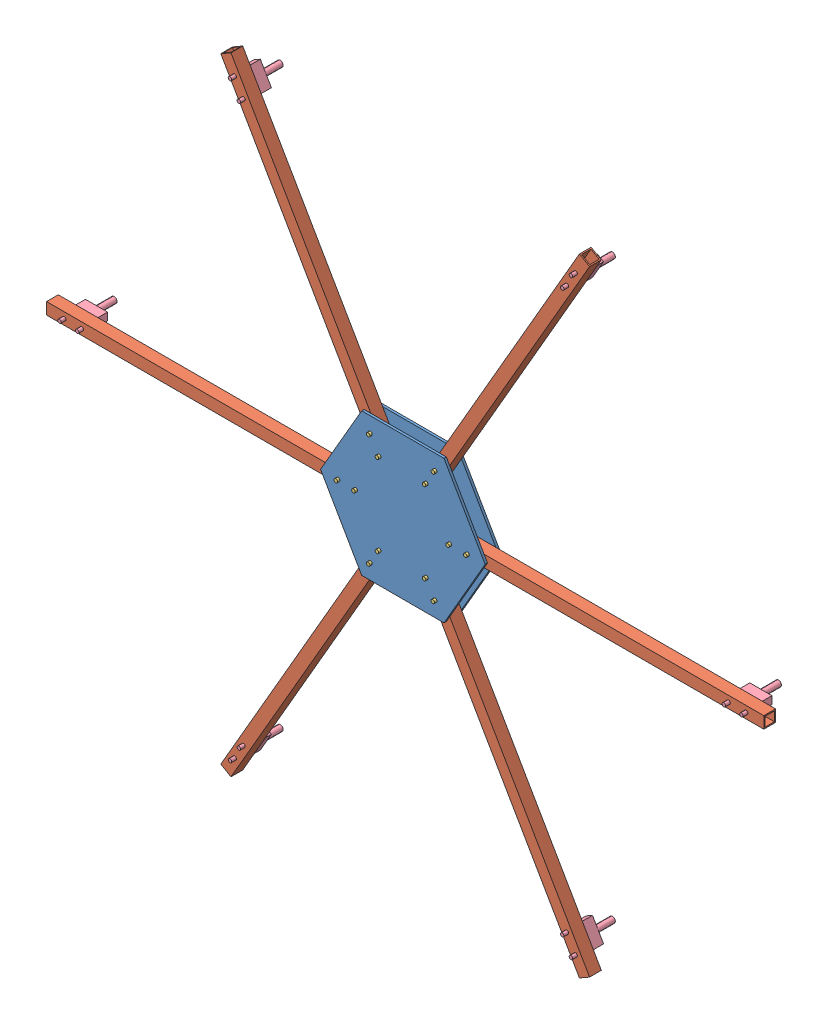
SolidWorks assembly carbonframe, configuration Default. Lengths in mm.
Overall size (610.11 533.37 39).
26 component instances, 4 part files, 63 mates.
Components (placement in the parent):
- carbonfiberplate-1: carbonfiberplate [Default] at (50.332 74.6713 106.3835) size (140 121.24 2)
- carbonfiberarm-2: carbonfiberarm [Default] at (-254.7472 74.717 113.3835) x (0 1 0) z (1 0 0) size (10 10 280)
- carbonfiberarm-3: carbonfiberarm [Default] at (-102.2208 -189.4665 113.3835) x (0.866025 -0.5 0) z (0.5 0.866025 0) size (10 10 280)
- carbonfiberarm-4: carbonfiberarm [Default] at (355.3584 74.717 113.3835) x (0 1 0) z (-1 0 0) size (10 10 280)
- carbonfiberarm-5: carbonfiberarm [Default] at (37.7792 96.4134 113.3835) x (0.866025 0.5 0) z (-0.5 0.866025 0) size (10 10 280)
- carbonfiberarm-6: carbonfiberarm [Default] at (62.832 96.4134 113.3835) x (0.866025 -0.5 0) z (0.5 0.866025 0) size (10 10 280)
- carbonfiberarm-7: carbonfiberarm [Default] at (62.832 53.0207 113.3835) x (0.866025 0.5 0) z (0.5 -0.866025 0) size (10 10 280)
- carbonfiberplate-2: carbonfiberplate [Default] at (50.332 74.6713 118.3835) size (140 121.24 2)
- nutfrcarbonframe-1: nutfrcarbonframe [Default] at (22.7792 122.3942 103.3835) size (6 6 19)
- nutfrcarbonframe-2: nutfrcarbonframe [Default] at (30.2792 109.4038 103.3835) size (6 6 19)
- nutfrcarbonframe-3: nutfrcarbonframe [Default] at (77.832 122.3942 103.3835) size (6 6 19)
- nutfrcarbonframe-4: nutfrcarbonframe [Default] at (70.332 109.4038 103.3835) size (6 6 19)
- nutfrcarbonframe-5: nutfrcarbonframe [Default] at (90.3584 74.717 103.3835) size (6 6 19)
- nutfrcarbonframe-6: nutfrcarbonframe [Default] at (70.332 40.0303 103.3835) size (6 6 19)
- nutfrcarbonframe-7: nutfrcarbonframe [Default] at (105.3584 74.717 103.3835) x (0.627916 0.778281 0) z (0 0 1) size (6 6 19)
- nutfrcarbonframe-8: nutfrcarbonframe [Default] at (77.832 27.0399 103.3835) x (0.998985 0.045038 0) z (0 0 1) size (6 6 19)
- nutfrcarbonframe-9: nutfrcarbonframe [Default] at (30.2792 40.0303 103.3835) size (6 6 19)
- nutfrcarbonframe-10: nutfrcarbonframe [Default] at (22.7792 27.0399 103.3835) size (6 6 19)
- nutfrcarbonframe-11: nutfrcarbonframe [Default] at (10.2528 74.717 103.3835) size (6 6 19)
- nutfrcarbonframe-12: nutfrcarbonframe [Default] at (-4.7472 74.717 103.3835) size (6 6 19)
- motorcf-1: motorcf [Default] at (-87.2208 -163.4857 122.3835) x (-0.5 -0.866025 0) z (0 0 -1) size (18.85 6.42 39)
- motorcf-2: motorcf [Default] at (-224.7472 74.717 122.3835) x (-1 0 0) z (0 0 -1) size (18.85 6.42 39)
- motorcf-3: motorcf [Default] at (340.3584 74.717 122.3835) x (-1 0 0) z (0 0 -1) size (18.85 6.42 39)
- motorcf-4: motorcf [Default] at (187.832 -163.4857 122.3835) x (0.5 -0.866025 0) z (0 0 -1) size (18.85 6.42 39)
- motorcf-5: motorcf [Default] at (195.332 325.9101 122.3835) x (-0.5 -0.866025 0) z (0 0 -1) size (18.85 6.42 39)
- motorcf-6: motorcf [Default] at (-87.2208 312.9197 122.3835) x (-0.5 0.866025 0) z (0 0 -1) size (18.85 6.42 39)
Mates (geometry in assembly coordinates):
- Coincident1: coincident anti-aligned: plane of carbonfiberplate-1 through (50.332 74.6713 108.3835) normal (0 0 1); plane of carbonfiberarm-2 through (25.2528 69.717 108.3835) normal (0 0 -1)
- Coincident8: coincident aligned: circle of carbonfiberplate-1; circle of carbonfiberarm-2
- Coincident4: coincident anti-aligned: plane of carbonfiberplate-1 through (50.332 74.6713 108.3835) normal (0 0 1); plane of carbonfiberarm-3 through (33.4491 55.5207 108.3835) normal (0 0 -1)
- Coincident5: coincident anti-aligned: circle of carbonfiberplate-1; circle of carbonfiberarm-3
- Coincident6: coincident anti-aligned: circle of carbonfiberplate-1; circle of carbonfiberarm-3
- Coincident7: coincident anti-aligned: plane of carbonfiberplate-1 through (50.332 74.6713 108.3835) normal (0 0 1); plane of carbonfiberarm-5 through (-106.5509 336.4005 108.3835) normal (0 0 -1)
- Coincident9: coincident aligned: circle of carbonfiberplate-1; circle of carbonfiberarm-2
- Coincident10: coincident anti-aligned: circle of carbonfiberplate-1; circle of carbonfiberarm-5
- Coincident11: coincident anti-aligned: circle of carbonfiberplate-1; circle of carbonfiberarm-5
- Coincident12: coincident anti-aligned: plane of carbonfiberplate-1 through (50.332 74.6713 108.3835) normal (0 0 1); plane of carbonfiberarm-4 through (75.3584 69.717 108.3835) normal (0 0 -1)
- Coincident13: coincident anti-aligned: circle of carbonfiberplate-1; circle of carbonfiberarm-4
- Coincident14: coincident anti-aligned: circle of carbonfiberplate-1; circle of carbonfiberarm-4
- Coincident15: coincident anti-aligned: plane of carbonfiberplate-1 through (50.332 74.6713 108.3835) normal (0 0 1); plane of carbonfiberarm-6 through (198.5019 341.4005 108.3835) normal (0 0 -1)
- Coincident16: coincident anti-aligned: circle of carbonfiberplate-1; circle of carbonfiberarm-6
- Coincident17: coincident anti-aligned: circle of carbonfiberplate-1; circle of carbonfiberarm-6
- Coincident18: coincident anti-aligned: plane of carbonfiberplate-1 through (50.332 74.6713 108.3835) normal (0 0 1); plane of carbonfiberarm-7 through (198.5019 -191.9665 108.3835) normal (0 0 -1)
- Coincident19: coincident aligned: circle of carbonfiberplate-1; circle of carbonfiberarm-7
- Coincident20: coincident aligned: circle of carbonfiberplate-1; circle of carbonfiberarm-7
- Coincident21: coincident anti-aligned: plane of carbonfiberarm-6 through (198.5019 341.4005 118.3835) normal (0 0 1); plane of carbonfiberplate-2 through (50.332 74.6713 118.3835) normal (0 0 -1)
- Coincident22: coincident anti-aligned: circle of carbonfiberarm-4; circle of carbonfiberplate-2
- Coincident23: coincident anti-aligned: circle of carbonfiberarm-4; circle of carbonfiberplate-2
- Concentric5: concentric aligned: cylinder of carbonfiberplate-1 through (22.7792 122.3942 108.3835) axis (0 0 -1) radius 1.5; cylinder of nutfrcarbonframe-1 through (22.7792 122.3942 122.3835) axis (0 0 -1) radius 1.5
- Coincident24: coincident anti-aligned: plane of carbonfiberplate-1 through (50.332 74.6713 106.3835) normal (0 0 -1); plane of nutfrcarbonframe-1 through (22.7792 122.3942 106.3835) normal (0 0 1)
- Concentric6: concentric aligned: cylinder of carbonfiberplate-1 through (30.2792 109.4038 108.3835) axis (0 0 -1) radius 1.5; cylinder of nutfrcarbonframe-2 through (30.2792 109.4038 122.3835) axis (0 0 -1) radius 1.5
- Coincident25: coincident anti-aligned: plane of carbonfiberplate-1 through (50.332 74.6713 106.3835) normal (0 0 -1); plane of nutfrcarbonframe-2 through (30.2792 109.4038 106.3835) normal (0 0 1)
- Concentric7: concentric aligned: cylinder of carbonfiberplate-1 through (77.832 122.3942 108.3835) axis (0 0 -1) radius 1.5; cylinder of nutfrcarbonframe-3 through (77.832 122.3942 122.3835) axis (0 0 -1) radius 1.5
- Coincident26: coincident anti-aligned: plane of carbonfiberplate-1 through (50.332 74.6713 106.3835) normal (0 0 -1); plane of nutfrcarbonframe-3 through (77.832 122.3942 106.3835) normal (0 0 1)
- Concentric8: concentric aligned: cylinder of carbonfiberplate-1 through (70.332 109.4038 108.3835) axis (0 0 -1) radius 1.5; cylinder of nutfrcarbonframe-4 through (70.332 109.4038 122.3835) axis (0 0 -1) radius 1.5
- Coincident27: coincident anti-aligned: plane of carbonfiberplate-1 through (50.332 74.6713 106.3835) normal (0 0 -1); plane of nutfrcarbonframe-4 through (70.332 109.4038 106.3835) normal (0 0 1)
- Concentric9: concentric aligned: cylinder of carbonfiberplate-1 through (90.3584 74.717 108.3835) axis (0 0 -1) radius 1.5; cylinder of nutfrcarbonframe-5 through (90.3584 74.717 122.3835) axis (0 0 -1) radius 1.5
- Coincident28: coincident anti-aligned: plane of carbonfiberplate-1 through (50.332 74.6713 106.3835) normal (0 0 -1); plane of nutfrcarbonframe-5 through (90.3584 74.717 106.3835) normal (0 0 1)
- Concentric10: concentric aligned: cylinder of carbonfiberplate-1 through (105.3584 74.717 108.3835) axis (0 0 -1) radius 1.5; cylinder of nutfrcarbonframe-7 through (105.3584 74.717 122.3835) axis (0 0 -1) radius 1.5
- Coincident29: coincident anti-aligned: plane of carbonfiberplate-1 through (50.332 74.6713 106.3835) normal (0 0 -1); plane of nutfrcarbonframe-7 through (105.3584 74.717 106.3835) normal (0 0 1)
- Concentric11: concentric aligned: cylinder of carbonfiberplate-1 through (77.832 27.0399 108.3835) axis (0 0 -1) radius 1.5; cylinder of nutfrcarbonframe-8 through (77.832 27.0399 122.3835) axis (0 0 -1) radius 1.5
- Coincident30: coincident anti-aligned: plane of carbonfiberplate-1 through (50.332 74.6713 106.3835) normal (0 0 -1); plane of nutfrcarbonframe-8 through (77.832 27.0399 106.3835) normal (0 0 1)
- Concentric12: concentric aligned: cylinder of carbonfiberplate-1 through (70.332 40.0303 108.3835) axis (0 0 -1) radius 1.5; cylinder of nutfrcarbonframe-6 through (70.332 40.0303 122.3835) axis (0 0 -1) radius 1.5
- Coincident31: coincident anti-aligned: plane of carbonfiberplate-1 through (50.332 74.6713 106.3835) normal (0 0 -1); plane of nutfrcarbonframe-6 through (70.332 40.0303 106.3835) normal (0 0 1)
- Concentric13: concentric aligned: cylinder of carbonfiberplate-1 through (30.2792 40.0303 108.3835) axis (0 0 -1) radius 1.5; cylinder of nutfrcarbonframe-9 through (30.2792 40.0303 122.3835) axis (0 0 -1) radius 1.5
- Coincident33: coincident anti-aligned: plane of carbonfiberplate-1 through (50.332 74.6713 106.3835) normal (0 0 -1); plane of nutfrcarbonframe-9 through (30.2792 40.0303 106.3835) normal (0 0 1)
- Concentric14: concentric aligned: cylinder of carbonfiberplate-1 through (22.7792 27.0399 108.3835) axis (0 0 -1) radius 1.5; cylinder of nutfrcarbonframe-10 through (22.7792 27.0399 122.3835) axis (0 0 -1) radius 1.5
- Coincident34: coincident anti-aligned: plane of carbonfiberplate-1 through (50.332 74.6713 106.3835) normal (0 0 -1); plane of nutfrcarbonframe-10 through (22.7792 27.0399 106.3835) normal (0 0 1)
- Concentric15: concentric aligned: cylinder of carbonfiberplate-1 through (10.2528 74.717 108.3835) axis (0 0 -1) radius 1.5; cylinder of nutfrcarbonframe-11 through (10.2528 74.717 122.3835) axis (0 0 -1) radius 1.5
- Coincident35: coincident anti-aligned: plane of carbonfiberplate-1 through (50.332 74.6713 106.3835) normal (0 0 -1); plane of nutfrcarbonframe-11 through (10.2528 74.717 106.3835) normal (0 0 1)
- Concentric16: concentric aligned: cylinder of carbonfiberplate-1 through (-4.7472 74.717 108.3835) axis (0 0 -1) radius 1.5; cylinder of nutfrcarbonframe-12 through (-4.7472 74.717 122.3835) axis (0 0 -1) radius 1.5
- Coincident36: coincident anti-aligned: plane of carbonfiberplate-1 through (50.332 74.6713 106.3835) normal (0 0 -1); plane of nutfrcarbonframe-12 through (-4.7472 74.717 106.3835) normal (0 0 1)
- Coincident37: coincident: plane of carbonfiberarm-3 through (33.4491 55.5207 108.3835) normal (0 0 -1); plane of motorcf-1 through (-87.2208 -163.4857 108.3835) normal (0 0 1)
- Coincident38: coincident: circle of carbonfiberarm-3; circle of motorcf-1
- Coincident39: coincident aligned: circle of carbonfiberarm-3; circle of motorcf-1
- Coincident40: coincident: plane of carbonfiberarm-7 through (198.5019 -191.9665 108.3835) normal (0 0 -1); plane of motorcf-4 through (187.832 -163.4857 108.3835) normal (0 0 1)
- Coincident41: coincident: circle of carbonfiberarm-7; circle of motorcf-4
- Coincident42: coincident aligned: circle of carbonfiberarm-7; circle of motorcf-4
- Coincident43: coincident: plane of carbonfiberarm-4 through (75.3584 69.717 108.3835) normal (0 0 -1); plane of motorcf-3 through (340.3584 74.717 108.3835) normal (0 0 1)
- Coincident44: coincident: circle of carbonfiberarm-4; circle of motorcf-3
- Coincident45: coincident aligned: circle of carbonfiberarm-4; circle of motorcf-3
- Coincident46: coincident: plane of carbonfiberarm-6 through (198.5019 341.4005 108.3835) normal (0 0 -1); plane of motorcf-5 through (195.332 325.9101 108.3835) normal (0 0 1)
- Coincident47: coincident: circle of carbonfiberarm-6; circle of motorcf-5
- Coincident48: coincident aligned: circle of carbonfiberarm-6; circle of motorcf-5
- Coincident49: coincident: plane of carbonfiberarm-5 through (-106.5509 336.4005 108.3835) normal (0 0 -1); plane of motorcf-6 through (-87.2208 312.9197 108.3835) normal (0 0 1)
- Coincident50: coincident: circle of carbonfiberarm-5; circle of motorcf-6
- Coincident51: coincident anti-aligned: circle of carbonfiberarm-5; circle of motorcf-6
- Coincident52: coincident: plane of carbonfiberarm-2 through (25.2528 69.717 108.3835) normal (0 0 -1); plane of motorcf-2 through (-224.7472 74.717 108.3835) normal (0 0 1)
- Coincident53: coincident: circle of carbonfiberarm-2; circle of motorcf-2
- Coincident54: coincident aligned: circle of carbonfiberarm-2; circle of motorcf-2
